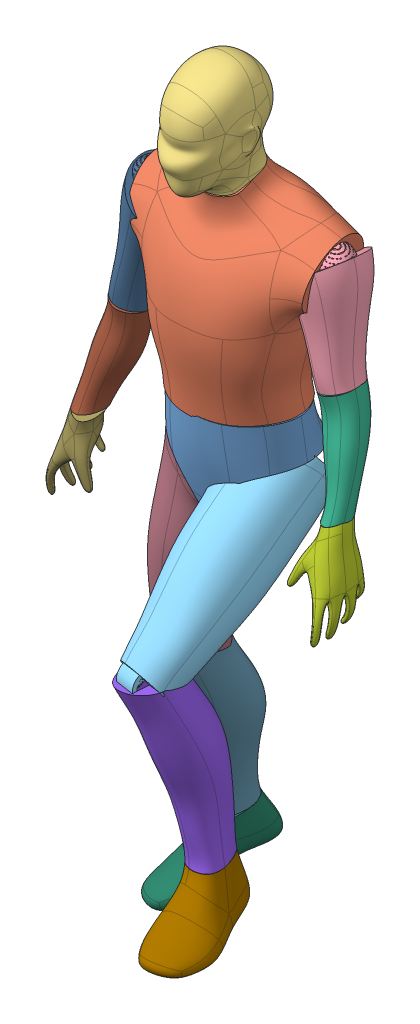
SolidWorks assembly Manikin1, configuration Default. Lengths in mm.
Overall size (779.61 1810.1 617.9).
15 component instances, 15 part files, 20 mates.
Components (placement in the parent):
- Hips-1: Hips [Default] at origin size (295.24 313.39 270.97)
- Torso-1: Torso [Default] at (-29.1895 18.5281 -268.9557) x (0.995716 0.002037 -0.092438) z (0.092349 -0.071067 0.993187) size (460.89 555.97 263.41)
- Head-2: Head [Default] at (-35.3994 3.8201 -64.7195) x (0.99996 -0.00842 0.002952) z (-0.003142 -0.022585 0.99974) size (157.49 285.21 225.45)
- ArmLeftUpper-1: ArmLeftUpper [Default] at (-2789.9904 1354.2797 -616.211) x (0.699144 -0.708077 0.099124) z (-0.173701 -0.033728 0.984221) size (245.85 241.52 164.39)
- LegLeftUpper-1: LegLeftUpper [Default] at (-651.3375 1438.003 2904.7833) x (0.980254 -0.042164 0.193196) z (-0.079831 0.809466 0.581715) size (217.98 507.99 239.38)
- ArmLeftFore-1: ArmLeftFore [Default] at (-2774.6323 1365.4227 -714.6365) x (0.707626 -0.704894 0.048893) z (-0.158512 -0.090931 0.983161) size (231.54 177.84 142.38)
- ArmLeftHand-1: ArmLeftHand [Default] at (-1936.929 562.4053 -725.019) x (0.885934 -0.459942 0.059786) z (-0.134029 -0.130474 0.982351) size (149.66 182.81 147.58)
- LegLeftLower-1: LegLeftLower [Default] at (-243.4164 192.3507 24.6626) x (0.988229 -0.068421 0.136831) z (-0.14208 -0.07885 0.98671) size (171.81 443.68 193.78)
- LegLeftFoot-1: LegLeftFoot [Default] at (-261.8497 185.3432 152.4364) x (0.987841 -0.068574 0.139525) z (-0.142052 -0.033453 0.989294) size (154.71 147.12 252.53)
- ArmRightUpper-1: ArmRightUpper [Default] at (2833.3521 1349.4619 519.7345) x (0.711137 0.701856 -0.04102) z (-0.054094 0.112795 0.992145) size (246.03 241.06 163.63)
- ArmRightFore-1: ArmRightFore [Default] at (2854.7947 1351.048 269.4164) x (0.701784 0.707122 0.08647) z (-0.091697 -0.030706 0.995313) size (231.51 177.54 142.76)
- ArmRightHand-1: ArmRightHand [Default] at (1627.5665 608.1197 -1273.5362) x (0.931008 0.283533 0.229854) z (-0.087727 -0.437455 0.894951) size (149.56 182.72 147.2)
- LegRightUpper-1: LegRightUpper [Default] at (453.5133 47.3786 416.4771) x (0.992212 0.123602 -0.015443) z (0.001079 0.115439 0.993314) size (216.84 507.94 244.77)
- LegRightLower-1: LegRightLower [Default] at (446.9718 61.9807 -286.2847) x (0.992319 0.1237 -0.001517) z (0.014171 -0.101475 0.994737) size (171.15 451.19 193.59)
- LegRightFoot-1: LegRightFoot [Default] at (437.459 153.0952 -765.4297) x (0.99252 0.121784 0.008585) z (0.024764 -0.26968 0.962631) size (155.81 152.18 252.53)
Mates (geometry in assembly coordinates):
- Concentric1: concentric: sphere of Hips-1; sphere of Torso-1
- Concentric2: concentric: sphere of Torso-1; sphere of Head-2
- Concentric3: concentric: sphere of Torso-1; sphere of ArmLeftUpper-1
- Concentric4: concentric: sphere of Hips-1; sphere of LegLeftUpper-1
- Coincident1: coincident aligned: plane of ArmLeftUpper-1 through (222.7171 3866.8899 84.1743) normal (0.952127 0.24954 0.176588); plane of ArmLeftFore-1 through (210.8198 3911.7849 84.8798) normal (0.952127 0.24954 0.176588)
- Concentric6: concentric anti-aligned: cylinder of ArmLeftUpper-1 through (216.3275 3891.4714 83.889) axis (0.952127 0.24954 0.176588) radius 25.4; cylinder of ArmLeftFore-1 through (192.1434 3885.1331 79.4037) axis (-0.952127 -0.24954 -0.176588) radius 21.0702
- Concentric7: concentric: sphere of ArmLeftFore-1; sphere of ArmLeftHand-1
- Coincident2: coincident aligned: plane of LegLeftUpper-1 through (100.8086 3406.8109 421.1995) normal (0.989832 -0.004548 0.142166); plane of LegLeftLower-1 through (100.8086 3406.8109 421.1995) normal (0.989832 -0.004548 0.142166)
- Concentric8: concentric aligned: cylinder of LegLeftUpper-1 through (57.5344 3407.0097 414.9842) axis (-0.989832 0.004548 -0.142166) radius 34.925; cylinder of LegLeftLower-1 through (57.5446 3407.0097 414.9857) axis (-0.989832 0.004548 -0.142166) radius 25.4
- Coincident3: coincident aligned: plane of LegLeftLower-1 through (153.0315 3023.2883 307.9739) normal (0.989852 -0.008681 0.141839); plane of LegLeftFoot-1 through (153.0315 3023.2883 307.9739) normal (0.989852 -0.008681 0.141839)
- Concentric9: concentric aligned: cylinder of LegLeftLower-1 through (121.6703 3023.5634 303.4801) axis (-0.989852 0.008681 -0.141839) radius 25.4; cylinder of LegLeftFoot-1 through (121.643 3023.5636 303.4762) axis (-0.989852 0.008681 -0.141839) radius 20.32
- Concentric10: concentric: sphere of Torso-1; sphere of ArmRightUpper-1
- Coincident4: coincident aligned: plane of ArmRightUpper-1 through (-225.7492 3893.0264 145.6947) normal (-0.96459 0.250968 -0.081124); plane of ArmRightFore-1 through (-225.7492 3893.0264 145.6947) normal (-0.96459 0.250968 -0.081124)
- Concentric11: concentric aligned: cylinder of ArmRightUpper-1 through (-225.7492 3893.0264 145.6947) axis (-0.96459 0.250968 -0.081124) radius 25.4; cylinder of ArmRightFore-1 through (-225.7492 3893.0264 145.6947) axis (-0.96459 0.250968 -0.081124) radius 21.082
- Concentric12: concentric: sphere of ArmRightFore-1; sphere of ArmRightHand-1
- Concentric13: concentric: sphere of Hips-1; sphere of LegRightUpper-1
- Coincident5: coincident aligned: plane of LegRightUpper-1 through (-80.669 3243.3076 135.1363) normal (0.998154 0.060188 -0.008079); plane of LegRightLower-1 through (-80.669 3243.3076 135.1363) normal (0.998154 0.060188 -0.008079)
- Concentric14: concentric aligned: cylinder of LegRightUpper-1 through (-124.3065 3240.6762 135.4895) axis (-0.998154 -0.060188 0.008079) radius 34.925; cylinder of LegRightLower-1 through (-124.2962 3240.6769 135.4894) axis (-0.998154 -0.060188 0.008079) radius 32.7046
- Coincident6: coincident aligned: plane of LegRightLower-1 through (-108.087 2860.6379 7.1195) normal (0.997901 0.064305 -0.007656); plane of LegRightFoot-1 through (-108.087 2860.6379 7.1195) normal (0.997901 0.064305 -0.007656)
- Concentric15: concentric aligned: cylinder of LegRightLower-1 through (-139.7044 2858.6005 7.3621) axis (-0.997901 -0.064305 0.007656) radius 25.4; cylinder of LegRightFoot-1 through (-139.732 2858.5987 7.3623) axis (-0.997901 -0.064305 0.007656) radius 25.4
